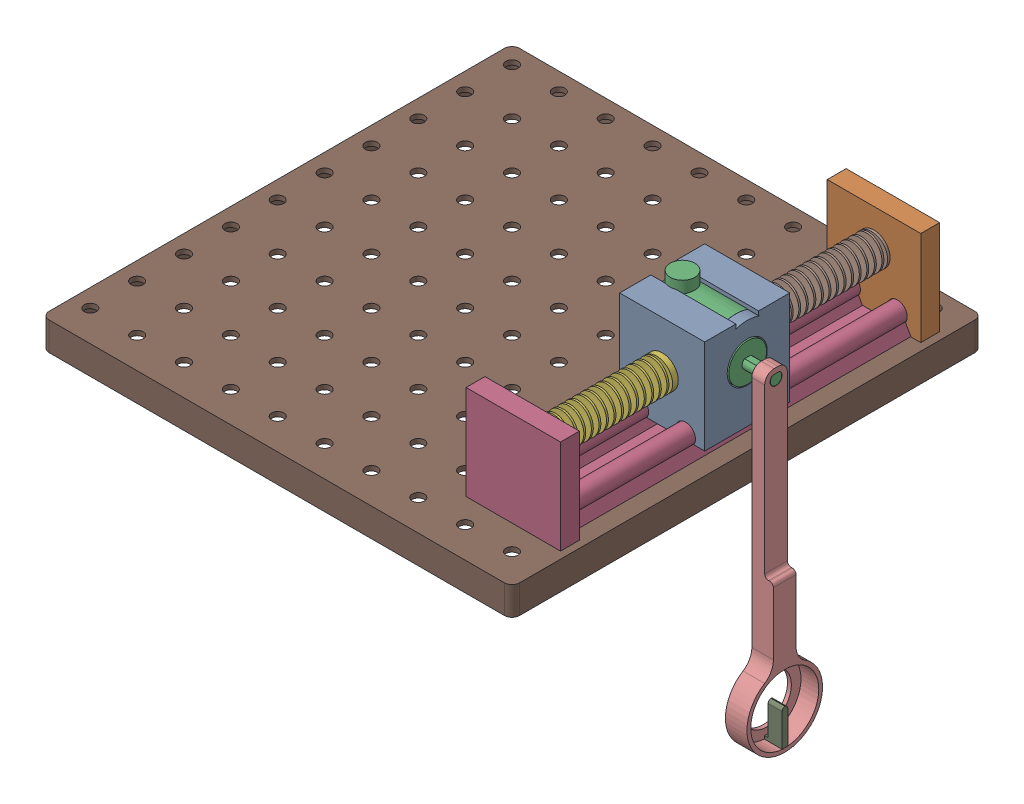
SolidWorks assembly xtheta Pendulum Assembly, configuration Default. Lengths in mm.
Overall size (262.66 193.92 249).
8 component instances, 7 part files, 14 mates.
Components (placement in the parent):
- encoder holder xtheta-1: encoder holder xtheta [Default] at (19.7994 80.841 35.5451) size (45 50 45)
- rail_2_wall-2: rail_2_wall [Default] at (29.9137 47.7431 -31.5549) x (-1 0 0) z (0 0 -1) size (49.5 50 10)
- taiss encoder-1: taiss encoder [Default] at (9.7861 82.4542 58.0451) x (0 0 -1) z (1 0 0) size (38.3 44.15 56)
- Linear_Rail_B-1: Linear_Rail_B [Default] at (15.6361 55.9392 -49.8549) size (50 50 198.9)
- example spring xtheta-6: example spring xtheta [Default] at (28.0361 78.2431 83.5451) x (1 0 0) z (0 -1 0) size (17.01 68.8 17)
- example spring xtheta-7: example spring xtheta [Default] at (28.0361 78.4392 -30.2549) x (1 0 0) z (0 -1 0) size (17.01 68.8 17)
- pendulum xtheta encoder-1: pendulum xtheta encoder [Default] at (58.9861 21.0363 58.0451) x (0 0 -1) z (1 0 0) size (40 174.08 11.41)
- pegboard-1: pegboard [Default] at (-53.1472 47.7431 51.5211) x (1 0 0) z (0 0 -1) size (249 15 249)
Mates (geometry in assembly coordinates):
- Concentric10: concentric aligned: cylinder of encoder holder xtheta-1 through (44.5361 82.4542 58.0451) axis (-1 0 0) radius 19.5; cylinder of taiss encoder-1 through (44.5361 82.4542 58.0451) axis (-1 0 0) radius 19.15
- Coincident8: coincident anti-aligned: plane of encoder holder xtheta-1 through (44.5361 82.4542 58.0451) normal (-1 0 0); plane of taiss encoder-1 through (44.5361 82.4542 58.0451) normal (1 0 0)
- Concentric12: concentric anti-aligned: cylinder of encoder holder xtheta-1 through (40.4361 55.9392 35.5451) axis (0 0 1) radius 5.2; cylinder of Linear_Rail_B-1 through (40.4361 55.9392 170.1451) axis (0 0 -1) radius 5
- Coincident10: coincident anti-aligned: plane of rail_2_wall-2 through (40.4361 55.9392 -39.5549) normal (0 0 1); plane of Linear_Rail_B-1 through (15.6361 55.9392 -39.5549) normal (0 0 -1)
- Concentric14: concentric anti-aligned: cylinder of rail_2_wall-2 through (40.4361 55.9392 -39.5549) axis (0 0 1) radius 5.2; cylinder of Linear_Rail_B-1 through (40.4361 55.9392 170.1451) axis (0 0 -1) radius 5
- Concentric15: concentric anti-aligned: cylinder of rail_2_wall-2 through (15.6361 55.9392 -39.5549) axis (0 0 1) radius 5.2; cylinder of Linear_Rail_B-1 through (15.6361 55.9392 170.1451) axis (0 0 -1) radius 5
- Concentric16: concentric anti-aligned: circle of Linear_Rail_B-1; circle of example spring xtheta-6
- Coincident12: coincident anti-aligned: plane of Linear_Rail_B-1 through (15.6361 55.9392 149.3451) normal (0 0 -1); plane of example spring xtheta-6 through (28.0361 78.2431 149.3451) normal (0 0 1)
- Coincident13: coincident anti-aligned: plane of encoder holder xtheta-1 through (19.7994 80.841 80.5451) normal (0 0 1); plane of example spring xtheta-6 through (28.0361 78.2431 80.5451) normal (0 0 -1)
- Coincident14: coincident anti-aligned: plane of encoder holder xtheta-1 through (19.7994 80.841 35.5451) normal (0 0 -1); plane of example spring xtheta-7 through (28.0361 78.4392 35.5451) normal (0 0 1)
- Coincident15: coincident anti-aligned: circle of encoder holder xtheta-1; circle of example spring xtheta-7
- Concentric17: concentric anti-aligned: cylinder of taiss encoder-1 through (65.7861 82.4542 58.0451) axis (-1 0 0) radius 3; cylinder of pendulum xtheta encoder-1 through (58.9861 82.4542 58.0451) axis (1 0 0) radius 3.1774
- Coincident16: coincident aligned: plane of taiss encoder-1 through (65.7861 82.4542 58.0451) normal (1 0 0); circle of pendulum xtheta encoder-1
- Coincident17: coincident anti-aligned: circle of Linear_Rail_B-1; circle of pegboard-1
